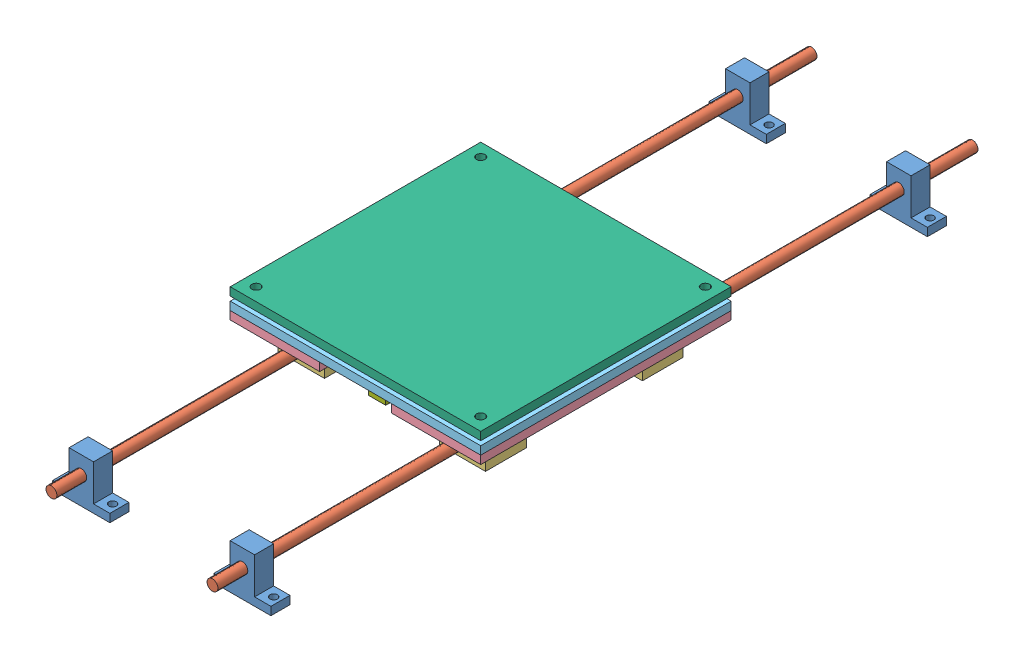
SolidWorks assembly rails_asm-bottom, configuration Default. Lengths in mm.
Overall size (184.15 52.16 558.8).
16 component instances, 7 part files, 40 mates.
Components (placement in the parent):
- Linear Rail Shaft Guide-1: Linear Rail Shaft Guide [Default] at (-12.9326 0.1821 32.8794) size (42 32.8 14)
- Linear Rail Shaft Guide-2: Linear Rail Shaft Guide [Default] at (-12.9326 0.1821 -449.7206) size (42 32.8 14)
- Linear Rail Shaft Guide-3: Linear Rail Shaft Guide [Default] at (-131.3326 0.1821 32.8794) size (42 32.8 14)
- Linear Rail Shaft Guide-4: Linear Rail Shaft Guide [Default] at (-131.3326 0.1821 -449.7206) size (42 32.8 14)
- 8mm rod-1: 8mm rod [Default] at (8.0674 20.1821 -489.9705) x (0.986971 -0.1609 0) z (0 0 1) size (8 8 558.8)
- 8mm rod-2: 8mm rod [Default] at (-110.3326 20.1821 -489.9705) x (0.967966 -0.251082 0) z (0 0 1) size (8 8 558.8)
- linear bearing platform-1: linear bearing platform [Default] at (-8.9326 9.1821 -144.8893) size (34 22 30)
- linear bearing platform-2: linear bearing platform [Default] at (-8.9326 9.1821 -260.2393) size (34 22 30)
- linear bearing platform-3: linear bearing platform [Default] at (-127.3326 9.1821 -144.8893) size (34 22 30)
- linear bearing platform-4: linear bearing platform [Default] at (-127.3326 9.1821 -260.2393) size (34 22 30)
- bottom plate-1: bottom plate [Default] at (-24.8076 37.1765 -279.6393) x (1 0 0) z (0 -1 0) size (65.75 184.15 5.99)
- bottom plate-2: bottom plate [Default] at (-143.2076 37.1765 -279.6393) x (1 0 0) z (0 -1 0) size (65.75 184.15 5.99)
- middle plate-1: middle plate [Default] at (-143.2076 37.1765 -95.4893) x (1 0 0) z (0 1 0) size (184.15 184.15 5.99)
- top layer-1: top layer [Default] at (-143.2076 46.3459 -95.4893) x (1 0 0) z (0 1 0) size (184.15 184.15 5.99)
- L-bracket belt mount-1: L-bracket belt mount [Default] at (-51.1326 37.1765 -257.4143) x (0 -1 0) z (-1 0 0) size (25.4 28.57 12.7)
- L-bracket belt mount-2: L-bracket belt mount [Default] at (-63.8326 37.1765 -117.7143) x (0 -1 0) z (1 0 0) size (25.4 28.57 12.7)
Mates (geometry in assembly coordinates):
- Concentric1: concentric aligned: cylinder of Linear Rail Shaft Guide-1 through (8.0674 20.1821 46.8794) axis (0 0 -1) radius 4; cylinder of 8mm rod-1 through (8.0674 20.1821 68.8295) axis (0 0 -1) radius 4
- Concentric2: concentric aligned: cylinder of Linear Rail Shaft Guide-2 through (8.0674 20.1821 -435.7206) axis (0 0 -1) radius 4; cylinder of 8mm rod-1 through (8.0674 20.1821 68.8295) axis (0 0 -1) radius 4
- Concentric3: concentric aligned: cylinder of Linear Rail Shaft Guide-3 through (-110.3326 20.1821 46.8794) axis (0 0 -1) radius 4; cylinder of 8mm rod-2 through (-110.3326 20.1821 68.8295) axis (0 0 -1) radius 4
- Concentric4: concentric aligned: cylinder of Linear Rail Shaft Guide-4 through (-110.3326 20.1821 -435.7206) axis (0 0 -1) radius 4; cylinder of 8mm rod-2 through (-110.3326 20.1821 68.8295) axis (0 0 -1) radius 4
- Coincident1: coincident: plane of Linear Rail Shaft Guide-1 through (-12.9326 0.1821 46.8794) normal (0 0 1); plane of Linear Rail Shaft Guide-3 through (-131.3326 0.1821 46.8794) normal (0 0 1)
- Coincident2: coincident aligned: plane of Linear Rail Shaft Guide-2 through (-12.9326 0.1821 -435.7206) normal (0 0 1); plane of Linear Rail Shaft Guide-4 through (-131.3326 0.1821 -435.7206) normal (0 0 1)
- Coincident3: coincident aligned: plane of 8mm rod-1 through (8.0674 20.1821 68.8295) normal (0 0 1); plane of 8mm rod-2 through (-110.3326 20.1821 68.8295) normal (0 0 1)
- Coincident4: coincident aligned: plane of Linear Rail Shaft Guide-1 through (-12.9326 0.1821 46.8794) normal (0 -1 0); plane of Linear Rail Shaft Guide-3 through (-131.3326 0.1821 46.8794) normal (0 -1 0)
- Coincident5: coincident aligned: plane of Linear Rail Shaft Guide-2 through (-12.9326 0.1821 -435.7206) normal (0 -1 0); plane of Linear Rail Shaft Guide-4 through (-131.3326 0.1821 -435.7206) normal (0 -1 0)
- Coincident6: coincident aligned: plane of Linear Rail Shaft Guide-1 through (-12.9326 0.1821 46.8794) normal (0 -1 0); plane of Linear Rail Shaft Guide-2 through (-12.9326 0.1821 -435.7206) normal (0 -1 0)
- Concentric5: concentric aligned: cylinder of 8mm rod-2 through (-110.3326 20.1821 68.8295) axis (0 0 -1) radius 4; cylinder of linear bearing platform-3 through (-110.3326 20.1821 -114.8893) axis (0 0 -1) radius 4
- Concentric6: concentric aligned: cylinder of 8mm rod-1 through (8.0674 20.1821 68.8295) axis (0 0 -1) radius 4; cylinder of linear bearing platform-1 through (8.0674 20.1821 -114.8893) axis (0 0 -1) radius 4
- Concentric7: concentric aligned: cylinder of 8mm rod-2 through (-110.3326 20.1821 68.8295) axis (0 0 -1) radius 4; cylinder of linear bearing platform-4 through (-110.3326 20.1821 -230.2393) axis (0 0 -1) radius 4
- Concentric8: concentric aligned: cylinder of 8mm rod-1 through (8.0674 20.1821 68.8295) axis (0 0 -1) radius 4; cylinder of linear bearing platform-2 through (8.0674 20.1821 -230.2393) axis (0 0 -1) radius 4
- Coincident7: coincident aligned: plane of linear bearing platform-2 through (-8.9326 31.1821 -230.2393) normal (0 1 0); plane of linear bearing platform-4 through (-127.3326 31.1821 -230.2393) normal (0 1 0)
- Coincident8: coincident aligned: plane of linear bearing platform-2 through (-8.9326 9.1821 -230.2393) normal (0 0 1); plane of linear bearing platform-4 through (-127.3326 9.1821 -230.2393) normal (0 0 1)
- Coincident9: coincident aligned: plane of linear bearing platform-1 through (-8.9326 31.1821 -114.8893) normal (0 1 0); plane of linear bearing platform-3 through (-127.3326 31.1821 -114.8893) normal (0 1 0)
- Coincident10: coincident aligned: plane of linear bearing platform-1 through (-8.9326 9.1821 -114.8893) normal (0 0 1); plane of linear bearing platform-3 through (-127.3326 9.1821 -114.8893) normal (0 0 1)
- Coincident11: coincident aligned: plane of linear bearing platform-1 through (-8.9326 9.1821 -114.8893) normal (0 -1 0); plane of linear bearing platform-2 through (-8.9326 9.1821 -230.2393) normal (0 -1 0)
- Coincident12: coincident aligned: plane of linear bearing platform-3 through (-127.3326 9.1821 -114.8893) normal (0 -1 0); plane of linear bearing platform-4 through (-127.3326 9.1821 -230.2393) normal (0 -1 0)
- Parallel2: parallel aligned: plane of Linear Rail Shaft Guide-1 through (-0.9326 32.9821 46.8794) normal (0 1 0); plane of linear bearing platform-1 through (-8.9326 31.1821 -114.8893) normal (0 1 0)
- Distance1: distance = 482.6 mm: moEndPointRef_w of Linear Rail Shaft Guide-1; moEndPointRef_w of Linear Rail Shaft Guide-2
- Coincident13: coincident anti-aligned: plane of linear bearing platform-1 through (-8.9326 31.1821 -114.8893) normal (0 1 0); plane of bottom plate-1 through (-24.8076 31.1821 -279.6393) normal (0 -1 0)
- Concentric9: concentric aligned: cylinder of linear bearing platform-2 through (-3.9326 9.1821 -254.2393) axis (0 1 0) radius 2; cylinder of bottom plate-1 through (-3.9326 31.1821 -254.2393) axis (0 1 0) radius 2
- Concentric10: concentric aligned: cylinder of linear bearing platform-1 through (-3.9326 9.1821 -138.8893) axis (0 1 0) radius 2; cylinder of bottom plate-1 through (-3.9326 31.1821 -138.8893) axis (0 1 0) radius 2
- Coincident14: coincident anti-aligned: plane of linear bearing platform-4 through (-127.3326 31.1821 -230.2393) normal (0 1 0); plane of bottom plate-2 through (-143.2076 31.1821 -279.6393) normal (0 -1 0)
- Concentric11: concentric aligned: cylinder of linear bearing platform-4 through (-122.3326 9.1821 -254.2393) axis (0 1 0) radius 2; cylinder of bottom plate-2 through (-122.3326 31.1821 -254.2393) axis (0 1 0) radius 2
- Concentric12: concentric aligned: cylinder of linear bearing platform-3 through (-122.3326 9.1821 -120.8893) axis (0 1 0) radius 2; cylinder of bottom plate-2 through (-122.3326 31.1821 -120.8893) axis (0 1 0) radius 2
- Coincident15: coincident anti-aligned: plane of bottom plate-1 through (-24.8076 37.1765 -279.6393) normal (0 1 0); plane of middle plate-1 through (-143.2076 37.1765 -95.4893) normal (0 -1 0)
- Concentric13: concentric anti-aligned: cylinder of bottom plate-2 through (-133.6826 31.1821 -270.1143) axis (0 1 0) radius 3.175; cylinder of middle plate-1 through (-133.6826 43.1709 -270.1143) axis (0 -1 0) radius 3.175
- Concentric14: concentric anti-aligned: cylinder of bottom plate-1 through (31.4174 31.1821 -270.1143) axis (0 1 0) radius 3.175; cylinder of middle plate-1 through (31.4174 43.1709 -270.1143) axis (0 -1 0) radius 3.175
- Distance2: distance = 3.175 mm anti-aligned: plane of top layer-1 through (-143.2076 46.3459 -95.4893) normal (0 -1 0); plane of middle plate-1 through (-143.2076 43.1709 -95.4893) normal (0 1 0)
- Concentric15: concentric aligned: cylinder of middle plate-1 through (-133.6826 43.1709 -270.1143) axis (0 -1 0) radius 3.175; cylinder of top layer-1 through (-133.6826 52.3403 -270.1143) axis (0 -1 0) radius 3.175
- Concentric16: concentric anti-aligned: cylinder of bottom plate-1 through (31.4174 31.1821 -105.0143) axis (0 1 0) radius 3.175; cylinder of top layer-1 through (31.4174 52.3403 -105.0143) axis (0 -1 0) radius 3.175
- Coincident17: coincident anti-aligned: plane of middle plate-1 through (-143.2076 37.1765 -95.4893) normal (0 -1 0); plane of L-bracket belt mount-1 through (-63.8326 37.1765 -257.4143) normal (0 1 0)
- Coincident18: coincident anti-aligned: plane of middle plate-1 through (-143.2076 37.1765 -95.4893) normal (0 -1 0); plane of L-bracket belt mount-2 through (-51.1326 37.1765 -117.7143) normal (0 1 0)
- Concentric21: concentric aligned: cylinder of middle plate-1 through (-57.4826 43.1709 -139.9393) axis (0 -1 0) radius 3.175; cylinder of L-bracket belt mount-2 through (-57.4826 37.1765 -139.9393) axis (0 -1 0) radius 3.175
- Parallel3: parallel anti-aligned: plane of bottom plate-2 through (-77.4576 31.1821 -279.6393) normal (1 0 0); plane of L-bracket belt mount-2 through (-63.8326 37.1765 -117.7143) normal (-1 0 0)
- Concentric22: concentric aligned: cylinder of middle plate-1 through (-57.4826 43.1709 -235.1893) axis (0 -1 0) radius 3.175; cylinder of L-bracket belt mount-1 through (-57.4826 37.1765 -235.1893) axis (0 -1 0) radius 3.175
- Concentric23: concentric aligned: cylinder of middle plate-1 through (-57.4826 43.1709 -247.8893) axis (0 -1 0) radius 3.175; cylinder of L-bracket belt mount-1 through (-57.4826 37.1765 -247.8893) axis (0 -1 0) radius 3.175
